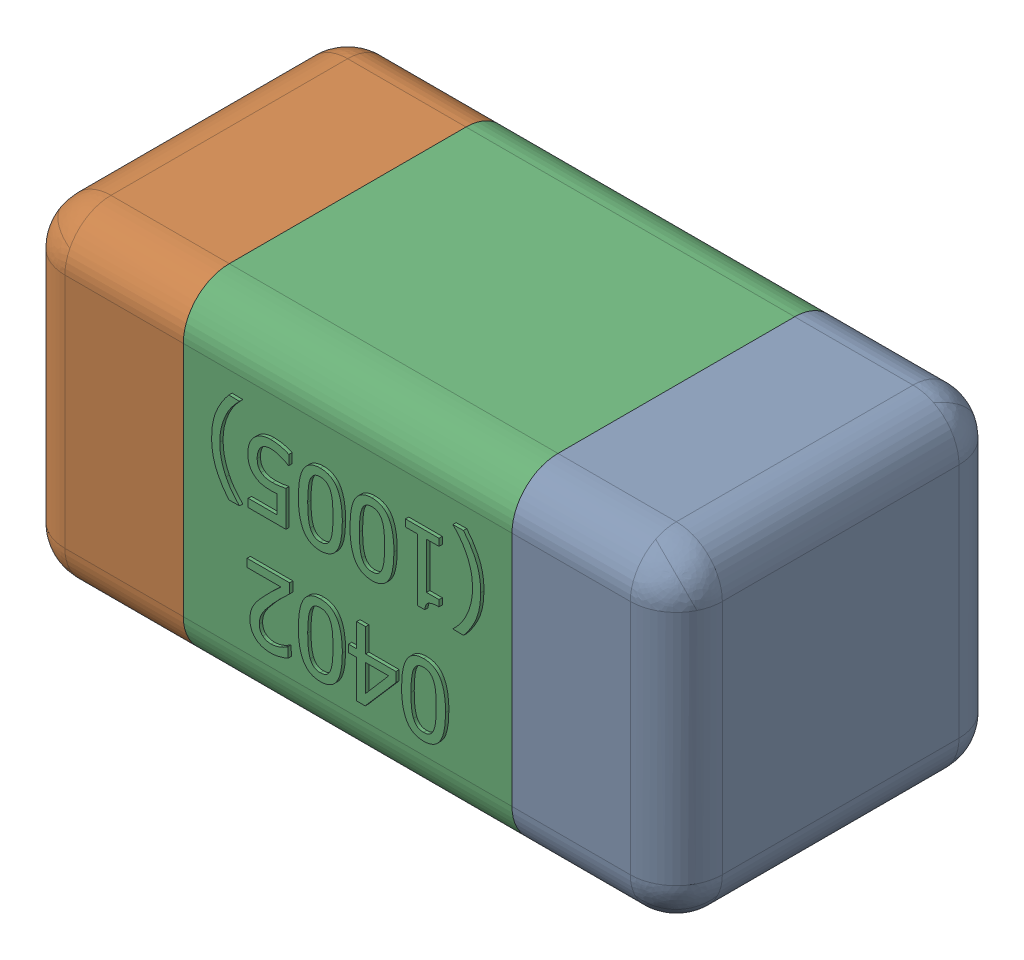
SolidWorks assembly C14, configuration Standard. Lengths in mm.
Overall size (1.01 0.51 0.51).
4 component instances, 3 part files, 0 mates.
Components (placement in the parent):
- C14-subassembly-1-1: C14-subassembly-1 [Standard] at (6.6999 -14 0) x (-1 0 0) z (0 0 1) size (1.01 0.51 0.51)
  - User Library-0402_Cap-1: User Library-0402_Cap [Standard] at origin size (0.26 0.51 0.51)
  - User Library-0402_Cap-1-1: User Library-0402_Cap-1 [Standard] at origin size (0.26 0.5 0.51)
  - User Library-0402_Cap-2-1: User Library-0402_Cap-2 [Standard] at origin size (0.5 0.5 0.51)
